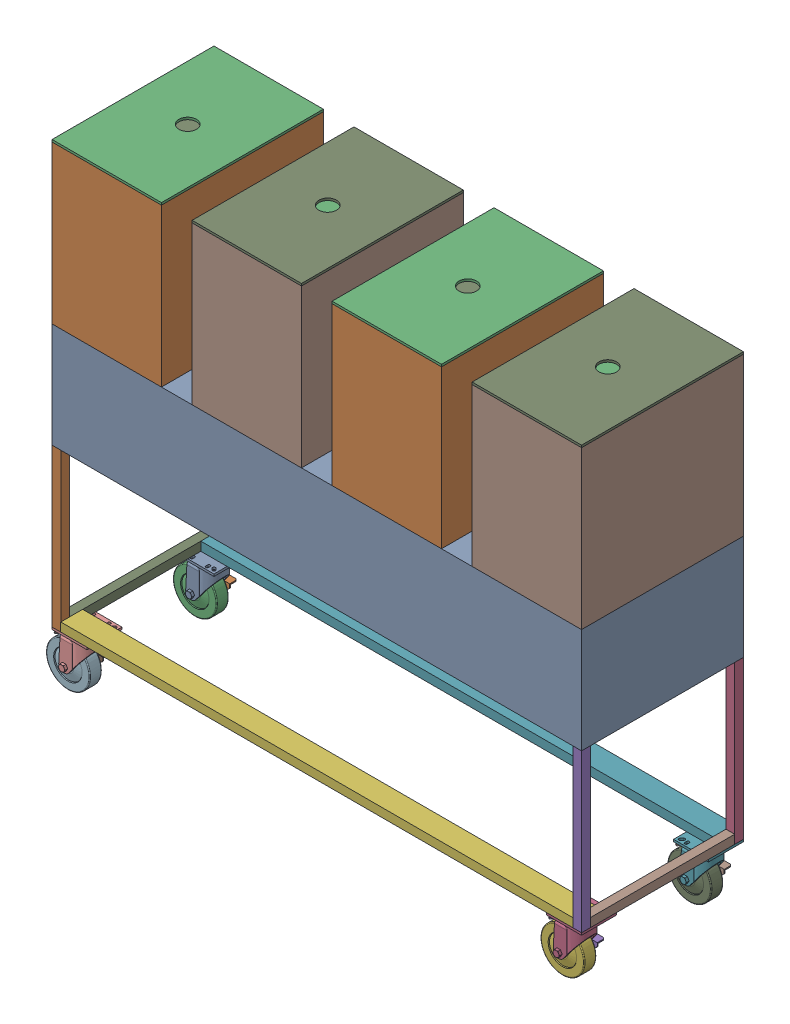
SolidWorks assembly Basic Assembly V1, configuration Default. Lengths in mm.
Overall size (1587.55 1393.83 474.36).
278 component instances, 11 part files, 3 mates.
Components (placement in the parent):
- Base Assembly-1: Base Assembly [Default] at (-1007.5115 421.629 254.1407) size (1587.55 930.27 474.36)
  - Base-1: Base [Default] at origin size (1536.7 304.8 469.9)
  - Base Leg-2: Base Leg [Default] at (0 -304.8 0) size (25.4 457.2 25.4)
  - Base Leg-3: Base Leg [Default] at (0 -304.8 -444.5) size (25.4 457.2 25.4)
  - Base Leg-4: Base Leg [Default] at (1511.3 -304.8 -444.5) size (25.4 457.2 25.4)
  - Base Leg-5: Base Leg [Default] at (1511.3 -304.8 0) size (25.4 457.2 25.4)
  - Long Leg Support-3: Long Leg Support [Default] at (25.146 -762 0) size (1486.15 25.4 63.5)
  - Long Leg Support-4: Long Leg Support [Default] at (25.146 -762 -406.4) size (1486.15 25.4 63.5)
  - Short Leg Support-3: Short Leg Support [Default] at (1536.7 -762 -21.336) x (0 0 -1) z (1 0 0) size (423.16 25.4 25.4)
  - Short Leg Support-4: Short Leg Support [Default] at (0 -762 -448.564) x (0 0 1) z (-1 0 0) size (423.16 25.4 25.4)
  - Caster Wheels-1: Caster Wheels [28925T74] at (50.75 -762 -50.75) size (152.35 168.28 105.96)
  - Caster Wheels-2: Caster Wheels [28925T74] at (50.75 -762 -419.15) size (152.35 168.28 105.96)
  - Caster Wheels-3: Caster Wheels [28925T74] at (1485.95 -762 -50.75) size (152.35 168.28 105.96)
  - Caster Wheels-4: Caster Wheels [28925T74] at (1485.95 -762 -419.15) size (152.35 168.28 105.96)
- Drying Racks Inside Chamber v1-4: Drying Racks Inside Chamber v1 [Default] at (-796.5651 486.7741 116.773) x (0 0 1) z (-1 0 0) size (469.9 463.55 317.5)
  - Stacked Tray Assembly-1: Stacked Tray Assembly [Default] at (-61.8185 38.0151 -6.3555) size (406.4 115.52 254)
    - Bottom Tray Assembly-1: Bottom Tray Assembly [Default] at (173.9076 -76.6729 -13.7937) size (406.4 76.81 254)
      - Perforated Tray-1: Perforated Tray [92725T36] at (-209.6714 56.3674 72.3455) size (406.4 0.61 254)
      - Tray Base-1: Tray Base [89825K319] at (-406.5214 -13.7874 72.3455) size (12.7 12.7 254)
      - Tray Base-2: Tray Base [89825K319] at (-12.8214 -13.7874 72.3455) size (12.7 12.7 254)
      - Tray Sides-1: Tray Sides [89825K319] at (-12.8214 24.3126 192.9955) x (1 0 0) z (0 -1 0) size (12.7 12.7 63.5)
      - Tray Sides-2: Tray Sides [89825K319] at (-406.5214 24.3126 192.9955) x (1 0 0) z (0 -1 0) size (12.7 12.7 63.5)
      - Tray Sides-3: Tray Sides [89825K319] at (-12.8214 24.3126 -48.3045) x (1 0 0) z (0 -1 0) size (12.7 12.7 63.5)
      - Tray Sides-4: Tray Sides [89825K319] at (-406.5214 24.3126 -48.3045) x (1 0 0) z (0 -1 0) size (12.7 12.7 63.5)
    - Additional Tray Assembly-1: Additional Tray Assembly [Default] at (65.2935 16.9544 6.2103) size (406.4 38.71 254)
      - Perforated Tray-1: Perforated Tray [92725T36] at (-101.0573 1.4498 52.3416) size (406.4 0.61 254)
      - Additional Tray Legs-1: Additional Tray Legs [8457K25] at (-299.4948 -17.905 174.5791) x (1 0 0) z (0 1 0) size (9.53 9.53 38.1)
      - Additional Tray Legs-2: Additional Tray Legs [8457K25] at (97.3802 -17.905 174.5791) x (1 0 0) z (0 1 0) size (9.53 9.53 38.1)
      - Additional Tray Legs-3: Additional Tray Legs [8457K25] at (-299.4948 -17.905 -69.8959) x (1 0 0) z (0 1 0) size (9.53 9.53 38.1)
      - Additional Tray Legs-4: Additional Tray Legs [8457K25] at (97.3802 -17.905 -69.8959) x (1 0 0) z (0 1 0) size (9.53 9.53 38.1)
    - Additional Tray Assembly-7: Additional Tray Assembly [Default] at (65.2935 55.0544 6.2103) size (406.4 38.71 254)
      - Perforated Tray-1: Perforated Tray [92725T36] at (-101.0573 1.4498 52.3416) size (406.4 0.61 254)
      - Additional Tray Legs-1: Additional Tray Legs [8457K25] at (-299.4948 -17.905 174.5791) x (1 0 0) z (0 1 0) size (9.53 9.53 38.1)
      - Additional Tray Legs-2: Additional Tray Legs [8457K25] at (97.3802 -17.905 174.5791) x (1 0 0) z (0 1 0) size (9.53 9.53 38.1)
      - Additional Tray Legs-3: Additional Tray Legs [8457K25] at (-299.4948 -17.905 -69.8959) x (1 0 0) z (0 1 0) size (9.53 9.53 38.1)
      - Additional Tray Legs-4: Additional Tray Legs [8457K25] at (97.3802 -17.905 -69.8959) x (1 0 0) z (0 1 0) size (9.53 9.53 38.1)
    - Additional Tray Assembly-8: Additional Tray Assembly [Default] at (65.2935 93.1544 6.2103) size (406.4 38.71 254)
      - Perforated Tray-1: Perforated Tray [92725T36] at (-101.0573 1.4498 52.3416) size (406.4 0.61 254)
      - Additional Tray Legs-1: Additional Tray Legs [8457K25] at (-299.4948 -17.905 174.5791) x (1 0 0) z (0 1 0) size (9.53 9.53 38.1)
      - Additional Tray Legs-2: Additional Tray Legs [8457K25] at (97.3802 -17.905 174.5791) x (1 0 0) z (0 1 0) size (9.53 9.53 38.1)
      - Additional Tray Legs-3: Additional Tray Legs [8457K25] at (-299.4948 -17.905 -69.8959) x (1 0 0) z (0 1 0) size (9.53 9.53 38.1)
      - Additional Tray Legs-4: Additional Tray Legs [8457K25] at (97.3802 -17.905 -69.8959) x (1 0 0) z (0 1 0) size (9.53 9.53 38.1)
    - Additional Tray Assembly-9: Additional Tray Assembly [Default] at (65.2935 131.2544 6.2103) size (406.4 38.71 254)
      - Perforated Tray-1: Perforated Tray [92725T36] at (-101.0573 1.4498 52.3416) size (406.4 0.61 254)
      - Additional Tray Legs-1: Additional Tray Legs [8457K25] at (-299.4948 -17.905 174.5791) x (1 0 0) z (0 1 0) size (9.53 9.53 38.1)
      - Additional Tray Legs-2: Additional Tray Legs [8457K25] at (97.3802 -17.905 174.5791) x (1 0 0) z (0 1 0) size (9.53 9.53 38.1)
      - Additional Tray Legs-3: Additional Tray Legs [8457K25] at (-299.4948 -17.905 -69.8959) x (1 0 0) z (0 1 0) size (9.53 9.53 38.1)
      - Additional Tray Legs-4: Additional Tray Legs [8457K25] at (97.3802 -17.905 -69.8959) x (1 0 0) z (0 1 0) size (9.53 9.53 38.1)
    - Additional Tray Assembly-10: Additional Tray Assembly [Default] at (65.2935 169.3544 6.2103) size (406.4 38.71 254)
      - Perforated Tray-1: Perforated Tray [92725T36] at (-101.0573 1.4498 52.3416) size (406.4 0.61 254)
      - Additional Tray Legs-1: Additional Tray Legs [8457K25] at (-299.4948 -17.905 174.5791) x (1 0 0) z (0 1 0) size (9.53 9.53 38.1)
      - Additional Tray Legs-2: Additional Tray Legs [8457K25] at (97.3802 -17.905 174.5791) x (1 0 0) z (0 1 0) size (9.53 9.53 38.1)
      - Additional Tray Legs-3: Additional Tray Legs [8457K25] at (-299.4948 -17.905 -69.8959) x (1 0 0) z (0 1 0) size (9.53 9.53 38.1)
      - Additional Tray Legs-4: Additional Tray Legs [8457K25] at (97.3802 -17.905 -69.8959) x (1 0 0) z (0 1 0) size (9.53 9.53 38.1)
    - Additional Tray Assembly-11: Additional Tray Assembly [Default] at (65.2935 207.4544 6.2103) size (406.4 38.71 254)
      - Perforated Tray-1: Perforated Tray [92725T36] at (-101.0573 1.4498 52.3416) size (406.4 0.61 254)
      - Additional Tray Legs-1: Additional Tray Legs [8457K25] at (-299.4948 -17.905 174.5791) x (1 0 0) z (0 1 0) size (9.53 9.53 38.1)
      - Additional Tray Legs-2: Additional Tray Legs [8457K25] at (97.3802 -17.905 174.5791) x (1 0 0) z (0 1 0) size (9.53 9.53 38.1)
      - Additional Tray Legs-3: Additional Tray Legs [8457K25] at (-299.4948 -17.905 -69.8959) x (1 0 0) z (0 1 0) size (9.53 9.53 38.1)
      - Additional Tray Legs-4: Additional Tray Legs [8457K25] at (97.3802 -17.905 -69.8959) x (1 0 0) z (0 1 0) size (9.53 9.53 38.1)
    - Additional Tray Assembly-12: Additional Tray Assembly [Default] at (65.2935 245.5544 6.2103) size (406.4 38.71 254)
      - Perforated Tray-1: Perforated Tray [92725T36] at (-101.0573 1.4498 52.3416) size (406.4 0.61 254)
      - Additional Tray Legs-1: Additional Tray Legs [8457K25] at (-299.4948 -17.905 174.5791) x (1 0 0) z (0 1 0) size (9.53 9.53 38.1)
      - Additional Tray Legs-2: Additional Tray Legs [8457K25] at (97.3802 -17.905 174.5791) x (1 0 0) z (0 1 0) size (9.53 9.53 38.1)
      - Additional Tray Legs-3: Additional Tray Legs [8457K25] at (-299.4948 -17.905 -69.8959) x (1 0 0) z (0 1 0) size (9.53 9.53 38.1)
      - Additional Tray Legs-4: Additional Tray Legs [8457K25] at (97.3802 -17.905 -69.8959) x (1 0 0) z (0 1 0) size (9.53 9.53 38.1)
    - Additional Tray Assembly-13: Additional Tray Assembly [Default] at (65.2935 283.6544 6.2103) size (406.4 38.71 254)
      - Perforated Tray-1: Perforated Tray [92725T36] at (-101.0573 1.4498 52.3416) size (406.4 0.61 254)
      - Additional Tray Legs-1: Additional Tray Legs [8457K25] at (-299.4948 -17.905 174.5791) x (1 0 0) z (0 1 0) size (9.53 9.53 38.1)
      - Additional Tray Legs-2: Additional Tray Legs [8457K25] at (97.3802 -17.905 174.5791) x (1 0 0) z (0 1 0) size (9.53 9.53 38.1)
      - Additional Tray Legs-3: Additional Tray Legs [8457K25] at (-299.4948 -17.905 -69.8959) x (1 0 0) z (0 1 0) size (9.53 9.53 38.1)
      - Additional Tray Legs-4: Additional Tray Legs [8457K25] at (97.3802 -17.905 -69.8959) x (1 0 0) z (0 1 0) size (9.53 9.53 38.1)
    - Additional Tray Assembly-14: Additional Tray Assembly [Default] at (65.2935 321.7544 6.2103) size (406.4 38.71 254)
      - Perforated Tray-1: Perforated Tray [92725T36] at (-101.0573 1.4498 52.3416) size (406.4 0.61 254)
      - Additional Tray Legs-1: Additional Tray Legs [8457K25] at (-299.4948 -17.905 174.5791) x (1 0 0) z (0 1 0) size (9.53 9.53 38.1)
      - Additional Tray Legs-2: Additional Tray Legs [8457K25] at (97.3802 -17.905 174.5791) x (1 0 0) z (0 1 0) size (9.53 9.53 38.1)
      - Additional Tray Legs-3: Additional Tray Legs [8457K25] at (-299.4948 -17.905 -69.8959) x (1 0 0) z (0 1 0) size (9.53 9.53 38.1)
      - Additional Tray Legs-4: Additional Tray Legs [8457K25] at (97.3802 -17.905 -69.8959) x (1 0 0) z (0 1 0) size (9.53 9.53 38.1)
  - Drying Chamber-1: Drying Chamber [Default] at (-326.1823 -65.1452 204.5964) x (1 0 0) z (0 1 0) size (469.9 317.5 457.2)
  - Drying Chamber Roof-1: Drying Chamber Roof [Default] at (-332.5323 392.0548 210.9464) size (469.9 6.35 317.5)
- Drying Racks Inside Chamber v1-5: Drying Racks Inside Chamber v1 [Default] at (-390.1651 486.7741 116.773) x (0 0 1) z (-1 0 0) size (469.9 463.55 317.5)
  - Stacked Tray Assembly-1: Stacked Tray Assembly [Default] at (-61.8185 38.0151 -6.3555) size (406.4 115.52 254)
    - Bottom Tray Assembly-1: Bottom Tray Assembly [Default] at (173.9076 -76.6729 -13.7937) size (406.4 76.81 254)
      - Perforated Tray-1: Perforated Tray [92725T36] at (-209.6714 56.3674 72.3455) size (406.4 0.61 254)
      - Tray Base-1: Tray Base [89825K319] at (-406.5214 -13.7874 72.3455) size (12.7 12.7 254)
      - Tray Base-2: Tray Base [89825K319] at (-12.8214 -13.7874 72.3455) size (12.7 12.7 254)
      - Tray Sides-1: Tray Sides [89825K319] at (-12.8214 24.3126 192.9955) x (1 0 0) z (0 -1 0) size (12.7 12.7 63.5)
      - Tray Sides-2: Tray Sides [89825K319] at (-406.5214 24.3126 192.9955) x (1 0 0) z (0 -1 0) size (12.7 12.7 63.5)
      - Tray Sides-3: Tray Sides [89825K319] at (-12.8214 24.3126 -48.3045) x (1 0 0) z (0 -1 0) size (12.7 12.7 63.5)
      - Tray Sides-4: Tray Sides [89825K319] at (-406.5214 24.3126 -48.3045) x (1 0 0) z (0 -1 0) size (12.7 12.7 63.5)
    - Additional Tray Assembly-1: Additional Tray Assembly [Default] at (65.2935 16.9544 6.2103) size (406.4 38.71 254)
      - Perforated Tray-1: Perforated Tray [92725T36] at (-101.0573 1.4498 52.3416) size (406.4 0.61 254)
      - Additional Tray Legs-1: Additional Tray Legs [8457K25] at (-299.4948 -17.905 174.5791) x (1 0 0) z (0 1 0) size (9.53 9.53 38.1)
      - Additional Tray Legs-2: Additional Tray Legs [8457K25] at (97.3802 -17.905 174.5791) x (1 0 0) z (0 1 0) size (9.53 9.53 38.1)
      - Additional Tray Legs-3: Additional Tray Legs [8457K25] at (-299.4948 -17.905 -69.8959) x (1 0 0) z (0 1 0) size (9.53 9.53 38.1)
      - Additional Tray Legs-4: Additional Tray Legs [8457K25] at (97.3802 -17.905 -69.8959) x (1 0 0) z (0 1 0) size (9.53 9.53 38.1)
    - Additional Tray Assembly-7: Additional Tray Assembly [Default] at (65.2935 55.0544 6.2103) size (406.4 38.71 254)
      - Perforated Tray-1: Perforated Tray [92725T36] at (-101.0573 1.4498 52.3416) size (406.4 0.61 254)
      - Additional Tray Legs-1: Additional Tray Legs [8457K25] at (-299.4948 -17.905 174.5791) x (1 0 0) z (0 1 0) size (9.53 9.53 38.1)
      - Additional Tray Legs-2: Additional Tray Legs [8457K25] at (97.3802 -17.905 174.5791) x (1 0 0) z (0 1 0) size (9.53 9.53 38.1)
      - Additional Tray Legs-3: Additional Tray Legs [8457K25] at (-299.4948 -17.905 -69.8959) x (1 0 0) z (0 1 0) size (9.53 9.53 38.1)
      - Additional Tray Legs-4: Additional Tray Legs [8457K25] at (97.3802 -17.905 -69.8959) x (1 0 0) z (0 1 0) size (9.53 9.53 38.1)
    - Additional Tray Assembly-8: Additional Tray Assembly [Default] at (65.2935 93.1544 6.2103) size (406.4 38.71 254)
      - Perforated Tray-1: Perforated Tray [92725T36] at (-101.0573 1.4498 52.3416) size (406.4 0.61 254)
      - Additional Tray Legs-1: Additional Tray Legs [8457K25] at (-299.4948 -17.905 174.5791) x (1 0 0) z (0 1 0) size (9.53 9.53 38.1)
      - Additional Tray Legs-2: Additional Tray Legs [8457K25] at (97.3802 -17.905 174.5791) x (1 0 0) z (0 1 0) size (9.53 9.53 38.1)
      - Additional Tray Legs-3: Additional Tray Legs [8457K25] at (-299.4948 -17.905 -69.8959) x (1 0 0) z (0 1 0) size (9.53 9.53 38.1)
      - Additional Tray Legs-4: Additional Tray Legs [8457K25] at (97.3802 -17.905 -69.8959) x (1 0 0) z (0 1 0) size (9.53 9.53 38.1)
    - Additional Tray Assembly-9: Additional Tray Assembly [Default] at (65.2935 131.2544 6.2103) size (406.4 38.71 254)
      - Perforated Tray-1: Perforated Tray [92725T36] at (-101.0573 1.4498 52.3416) size (406.4 0.61 254)
      - Additional Tray Legs-1: Additional Tray Legs [8457K25] at (-299.4948 -17.905 174.5791) x (1 0 0) z (0 1 0) size (9.53 9.53 38.1)
      - Additional Tray Legs-2: Additional Tray Legs [8457K25] at (97.3802 -17.905 174.5791) x (1 0 0) z (0 1 0) size (9.53 9.53 38.1)
      - Additional Tray Legs-3: Additional Tray Legs [8457K25] at (-299.4948 -17.905 -69.8959) x (1 0 0) z (0 1 0) size (9.53 9.53 38.1)
      - Additional Tray Legs-4: Additional Tray Legs [8457K25] at (97.3802 -17.905 -69.8959) x (1 0 0) z (0 1 0) size (9.53 9.53 38.1)
    - Additional Tray Assembly-10: Additional Tray Assembly [Default] at (65.2935 169.3544 6.2103) size (406.4 38.71 254)
      - Perforated Tray-1: Perforated Tray [92725T36] at (-101.0573 1.4498 52.3416) size (406.4 0.61 254)
      - Additional Tray Legs-1: Additional Tray Legs [8457K25] at (-299.4948 -17.905 174.5791) x (1 0 0) z (0 1 0) size (9.53 9.53 38.1)
      - Additional Tray Legs-2: Additional Tray Legs [8457K25] at (97.3802 -17.905 174.5791) x (1 0 0) z (0 1 0) size (9.53 9.53 38.1)
      - Additional Tray Legs-3: Additional Tray Legs [8457K25] at (-299.4948 -17.905 -69.8959) x (1 0 0) z (0 1 0) size (9.53 9.53 38.1)
      - Additional Tray Legs-4: Additional Tray Legs [8457K25] at (97.3802 -17.905 -69.8959) x (1 0 0) z (0 1 0) size (9.53 9.53 38.1)
    - Additional Tray Assembly-11: Additional Tray Assembly [Default] at (65.2935 207.4544 6.2103) size (406.4 38.71 254)
      - Perforated Tray-1: Perforated Tray [92725T36] at (-101.0573 1.4498 52.3416) size (406.4 0.61 254)
      - Additional Tray Legs-1: Additional Tray Legs [8457K25] at (-299.4948 -17.905 174.5791) x (1 0 0) z (0 1 0) size (9.53 9.53 38.1)
      - Additional Tray Legs-2: Additional Tray Legs [8457K25] at (97.3802 -17.905 174.5791) x (1 0 0) z (0 1 0) size (9.53 9.53 38.1)
      - Additional Tray Legs-3: Additional Tray Legs [8457K25] at (-299.4948 -17.905 -69.8959) x (1 0 0) z (0 1 0) size (9.53 9.53 38.1)
      - Additional Tray Legs-4: Additional Tray Legs [8457K25] at (97.3802 -17.905 -69.8959) x (1 0 0) z (0 1 0) size (9.53 9.53 38.1)
    - Additional Tray Assembly-12: Additional Tray Assembly [Default] at (65.2935 245.5544 6.2103) size (406.4 38.71 254)
      - Perforated Tray-1: Perforated Tray [92725T36] at (-101.0573 1.4498 52.3416) size (406.4 0.61 254)
      - Additional Tray Legs-1: Additional Tray Legs [8457K25] at (-299.4948 -17.905 174.5791) x (1 0 0) z (0 1 0) size (9.53 9.53 38.1)
      - Additional Tray Legs-2: Additional Tray Legs [8457K25] at (97.3802 -17.905 174.5791) x (1 0 0) z (0 1 0) size (9.53 9.53 38.1)
      - Additional Tray Legs-3: Additional Tray Legs [8457K25] at (-299.4948 -17.905 -69.8959) x (1 0 0) z (0 1 0) size (9.53 9.53 38.1)
      - Additional Tray Legs-4: Additional Tray Legs [8457K25] at (97.3802 -17.905 -69.8959) x (1 0 0) z (0 1 0) size (9.53 9.53 38.1)
    - Additional Tray Assembly-13: Additional Tray Assembly [Default] at (65.2935 283.6544 6.2103) size (406.4 38.71 254)
      - Perforated Tray-1: Perforated Tray [92725T36] at (-101.0573 1.4498 52.3416) size (406.4 0.61 254)
      - Additional Tray Legs-1: Additional Tray Legs [8457K25] at (-299.4948 -17.905 174.5791) x (1 0 0) z (0 1 0) size (9.53 9.53 38.1)
      - Additional Tray Legs-2: Additional Tray Legs [8457K25] at (97.3802 -17.905 174.5791) x (1 0 0) z (0 1 0) size (9.53 9.53 38.1)
      - Additional Tray Legs-3: Additional Tray Legs [8457K25] at (-299.4948 -17.905 -69.8959) x (1 0 0) z (0 1 0) size (9.53 9.53 38.1)
      - Additional Tray Legs-4: Additional Tray Legs [8457K25] at (97.3802 -17.905 -69.8959) x (1 0 0) z (0 1 0) size (9.53 9.53 38.1)
    - Additional Tray Assembly-14: Additional Tray Assembly [Default] at (65.2935 321.7544 6.2103) size (406.4 38.71 254)
      - Perforated Tray-1: Perforated Tray [92725T36] at (-101.0573 1.4498 52.3416) size (406.4 0.61 254)
      - Additional Tray Legs-1: Additional Tray Legs [8457K25] at (-299.4948 -17.905 174.5791) x (1 0 0) z (0 1 0) size (9.53 9.53 38.1)
      - Additional Tray Legs-2: Additional Tray Legs [8457K25] at (97.3802 -17.905 174.5791) x (1 0 0) z (0 1 0) size (9.53 9.53 38.1)
      - Additional Tray Legs-3: Additional Tray Legs [8457K25] at (-299.4948 -17.905 -69.8959) x (1 0 0) z (0 1 0) size (9.53 9.53 38.1)
      - Additional Tray Legs-4: Additional Tray Legs [8457K25] at (97.3802 -17.905 -69.8959) x (1 0 0) z (0 1 0) size (9.53 9.53 38.1)
  - Drying Chamber-1: Drying Chamber [Default] at (-326.1823 -65.1452 204.5964) x (1 0 0) z (0 1 0) size (469.9 317.5 457.2)
  - Drying Chamber Roof-1: Drying Chamber Roof [Default] at (-332.5323 392.0548 210.9464) size (469.9 6.35 317.5)
- Drying Racks Inside Chamber v1-6: Drying Racks Inside Chamber v1 [Default] at (16.2349 486.7741 116.773) x (0 0 1) z (-1 0 0) size (469.9 463.55 317.5)
  - Stacked Tray Assembly-1: Stacked Tray Assembly [Default] at (-61.8185 38.0151 -6.3555) size (406.4 115.52 254)
    - Bottom Tray Assembly-1: Bottom Tray Assembly [Default] at (173.9076 -76.6729 -13.7937) size (406.4 76.81 254)
      - Perforated Tray-1: Perforated Tray [92725T36] at (-209.6714 56.3674 72.3455) size (406.4 0.61 254)
      - Tray Base-1: Tray Base [89825K319] at (-406.5214 -13.7874 72.3455) size (12.7 12.7 254)
      - Tray Base-2: Tray Base [89825K319] at (-12.8214 -13.7874 72.3455) size (12.7 12.7 254)
      - Tray Sides-1: Tray Sides [89825K319] at (-12.8214 24.3126 192.9955) x (1 0 0) z (0 -1 0) size (12.7 12.7 63.5)
      - Tray Sides-2: Tray Sides [89825K319] at (-406.5214 24.3126 192.9955) x (1 0 0) z (0 -1 0) size (12.7 12.7 63.5)
      - Tray Sides-3: Tray Sides [89825K319] at (-12.8214 24.3126 -48.3045) x (1 0 0) z (0 -1 0) size (12.7 12.7 63.5)
      - Tray Sides-4: Tray Sides [89825K319] at (-406.5214 24.3126 -48.3045) x (1 0 0) z (0 -1 0) size (12.7 12.7 63.5)
    - Additional Tray Assembly-1: Additional Tray Assembly [Default] at (65.2935 16.9544 6.2103) size (406.4 38.71 254)
      - Perforated Tray-1: Perforated Tray [92725T36] at (-101.0573 1.4498 52.3416) size (406.4 0.61 254)
      - Additional Tray Legs-1: Additional Tray Legs [8457K25] at (-299.4948 -17.905 174.5791) x (1 0 0) z (0 1 0) size (9.53 9.53 38.1)
      - Additional Tray Legs-2: Additional Tray Legs [8457K25] at (97.3802 -17.905 174.5791) x (1 0 0) z (0 1 0) size (9.53 9.53 38.1)
      - Additional Tray Legs-3: Additional Tray Legs [8457K25] at (-299.4948 -17.905 -69.8959) x (1 0 0) z (0 1 0) size (9.53 9.53 38.1)
      - Additional Tray Legs-4: Additional Tray Legs [8457K25] at (97.3802 -17.905 -69.8959) x (1 0 0) z (0 1 0) size (9.53 9.53 38.1)
    - Additional Tray Assembly-7: Additional Tray Assembly [Default] at (65.2935 55.0544 6.2103) size (406.4 38.71 254)
      - Perforated Tray-1: Perforated Tray [92725T36] at (-101.0573 1.4498 52.3416) size (406.4 0.61 254)
      - Additional Tray Legs-1: Additional Tray Legs [8457K25] at (-299.4948 -17.905 174.5791) x (1 0 0) z (0 1 0) size (9.53 9.53 38.1)
      - Additional Tray Legs-2: Additional Tray Legs [8457K25] at (97.3802 -17.905 174.5791) x (1 0 0) z (0 1 0) size (9.53 9.53 38.1)
      - Additional Tray Legs-3: Additional Tray Legs [8457K25] at (-299.4948 -17.905 -69.8959) x (1 0 0) z (0 1 0) size (9.53 9.53 38.1)
      - Additional Tray Legs-4: Additional Tray Legs [8457K25] at (97.3802 -17.905 -69.8959) x (1 0 0) z (0 1 0) size (9.53 9.53 38.1)
    - Additional Tray Assembly-8: Additional Tray Assembly [Default] at (65.2935 93.1544 6.2103) size (406.4 38.71 254)
      - Perforated Tray-1: Perforated Tray [92725T36] at (-101.0573 1.4498 52.3416) size (406.4 0.61 254)
      - Additional Tray Legs-1: Additional Tray Legs [8457K25] at (-299.4948 -17.905 174.5791) x (1 0 0) z (0 1 0) size (9.53 9.53 38.1)
      - Additional Tray Legs-2: Additional Tray Legs [8457K25] at (97.3802 -17.905 174.5791) x (1 0 0) z (0 1 0) size (9.53 9.53 38.1)
      - Additional Tray Legs-3: Additional Tray Legs [8457K25] at (-299.4948 -17.905 -69.8959) x (1 0 0) z (0 1 0) size (9.53 9.53 38.1)
      - Additional Tray Legs-4: Additional Tray Legs [8457K25] at (97.3802 -17.905 -69.8959) x (1 0 0) z (0 1 0) size (9.53 9.53 38.1)
    - Additional Tray Assembly-9: Additional Tray Assembly [Default] at (65.2935 131.2544 6.2103) size (406.4 38.71 254)
      - Perforated Tray-1: Perforated Tray [92725T36] at (-101.0573 1.4498 52.3416) size (406.4 0.61 254)
      - Additional Tray Legs-1: Additional Tray Legs [8457K25] at (-299.4948 -17.905 174.5791) x (1 0 0) z (0 1 0) size (9.53 9.53 38.1)
      - Additional Tray Legs-2: Additional Tray Legs [8457K25] at (97.3802 -17.905 174.5791) x (1 0 0) z (0 1 0) size (9.53 9.53 38.1)
      - Additional Tray Legs-3: Additional Tray Legs [8457K25] at (-299.4948 -17.905 -69.8959) x (1 0 0) z (0 1 0) size (9.53 9.53 38.1)
      - Additional Tray Legs-4: Additional Tray Legs [8457K25] at (97.3802 -17.905 -69.8959) x (1 0 0) z (0 1 0) size (9.53 9.53 38.1)
    - Additional Tray Assembly-10: Additional Tray Assembly [Default] at (65.2935 169.3544 6.2103) size (406.4 38.71 254)
      - Perforated Tray-1: Perforated Tray [92725T36] at (-101.0573 1.4498 52.3416) size (406.4 0.61 254)
      - Additional Tray Legs-1: Additional Tray Legs [8457K25] at (-299.4948 -17.905 174.5791) x (1 0 0) z (0 1 0) size (9.53 9.53 38.1)
      - Additional Tray Legs-2: Additional Tray Legs [8457K25] at (97.3802 -17.905 174.5791) x (1 0 0) z (0 1 0) size (9.53 9.53 38.1)
      - Additional Tray Legs-3: Additional Tray Legs [8457K25] at (-299.4948 -17.905 -69.8959) x (1 0 0) z (0 1 0) size (9.53 9.53 38.1)
      - Additional Tray Legs-4: Additional Tray Legs [8457K25] at (97.3802 -17.905 -69.8959) x (1 0 0) z (0 1 0) size (9.53 9.53 38.1)
    - Additional Tray Assembly-11: Additional Tray Assembly [Default] at (65.2935 207.4544 6.2103) size (406.4 38.71 254)
      - Perforated Tray-1: Perforated Tray [92725T36] at (-101.0573 1.4498 52.3416) size (406.4 0.61 254)
      - Additional Tray Legs-1: Additional Tray Legs [8457K25] at (-299.4948 -17.905 174.5791) x (1 0 0) z (0 1 0) size (9.53 9.53 38.1)
      - Additional Tray Legs-2: Additional Tray Legs [8457K25] at (97.3802 -17.905 174.5791) x (1 0 0) z (0 1 0) size (9.53 9.53 38.1)
      - Additional Tray Legs-3: Additional Tray Legs [8457K25] at (-299.4948 -17.905 -69.8959) x (1 0 0) z (0 1 0) size (9.53 9.53 38.1)
      - Additional Tray Legs-4: Additional Tray Legs [8457K25] at (97.3802 -17.905 -69.8959) x (1 0 0) z (0 1 0) size (9.53 9.53 38.1)
    - Additional Tray Assembly-12: Additional Tray Assembly [Default] at (65.2935 245.5544 6.2103) size (406.4 38.71 254)
      - Perforated Tray-1: Perforated Tray [92725T36] at (-101.0573 1.4498 52.3416) size (406.4 0.61 254)
      - Additional Tray Legs-1: Additional Tray Legs [8457K25] at (-299.4948 -17.905 174.5791) x (1 0 0) z (0 1 0) size (9.53 9.53 38.1)
      - Additional Tray Legs-2: Additional Tray Legs [8457K25] at (97.3802 -17.905 174.5791) x (1 0 0) z (0 1 0) size (9.53 9.53 38.1)
      - Additional Tray Legs-3: Additional Tray Legs [8457K25] at (-299.4948 -17.905 -69.8959) x (1 0 0) z (0 1 0) size (9.53 9.53 38.1)
      - Additional Tray Legs-4: Additional Tray Legs [8457K25] at (97.3802 -17.905 -69.8959) x (1 0 0) z (0 1 0) size (9.53 9.53 38.1)
    - Additional Tray Assembly-13: Additional Tray Assembly [Default] at (65.2935 283.6544 6.2103) size (406.4 38.71 254)
      - Perforated Tray-1: Perforated Tray [92725T36] at (-101.0573 1.4498 52.3416) size (406.4 0.61 254)
      - Additional Tray Legs-1: Additional Tray Legs [8457K25] at (-299.4948 -17.905 174.5791) x (1 0 0) z (0 1 0) size (9.53 9.53 38.1)
      - Additional Tray Legs-2: Additional Tray Legs [8457K25] at (97.3802 -17.905 174.5791) x (1 0 0) z (0 1 0) size (9.53 9.53 38.1)
      - Additional Tray Legs-3: Additional Tray Legs [8457K25] at (-299.4948 -17.905 -69.8959) x (1 0 0) z (0 1 0) size (9.53 9.53 38.1)
      - Additional Tray Legs-4: Additional Tray Legs [8457K25] at (97.3802 -17.905 -69.8959) x (1 0 0) z (0 1 0) size (9.53 9.53 38.1)
    - Additional Tray Assembly-14: Additional Tray Assembly [Default] at (65.2935 321.7544 6.2103) size (406.4 38.71 254)
      - Perforated Tray-1: Perforated Tray [92725T36] at (-101.0573 1.4498 52.3416) size (406.4 0.61 254)
      - Additional Tray Legs-1: Additional Tray Legs [8457K25] at (-299.4948 -17.905 174.5791) x (1 0 0) z (0 1 0) size (9.53 9.53 38.1)
      - Additional Tray Legs-2: Additional Tray Legs [8457K25] at (97.3802 -17.905 174.5791) x (1 0 0) z (0 1 0) size (9.53 9.53 38.1)
      - Additional Tray Legs-3: Additional Tray Legs [8457K25] at (-299.4948 -17.905 -69.8959) x (1 0 0) z (0 1 0) size (9.53 9.53 38.1)
      - Additional Tray Legs-4: Additional Tray Legs [8457K25] at (97.3802 -17.905 -69.8959) x (1 0 0) z (0 1 0) size (9.53 9.53 38.1)
  - Drying Chamber-1: Drying Chamber [Default] at (-326.1823 -65.1452 204.5964) x (1 0 0) z (0 1 0) size (469.9 317.5 457.2)
  - Drying Chamber Roof-1: Drying Chamber Roof [Default] at (-332.5323 392.0548 210.9464) size (469.9 6.35 317.5)
- Drying Racks Inside Chamber v1-7: Drying Racks Inside Chamber v1 [Default] at (422.6349 486.7741 116.773) x (0 0 1) z (-1 0 0) size (469.9 463.55 317.5)
  - Stacked Tray Assembly-1: Stacked Tray Assembly [Default] at (-61.8185 38.0151 -6.3555) size (406.4 115.52 254)
    - Bottom Tray Assembly-1: Bottom Tray Assembly [Default] at (173.9076 -76.6729 -13.7937) size (406.4 76.81 254)
      - Perforated Tray-1: Perforated Tray [92725T36] at (-209.6714 56.3674 72.3455) size (406.4 0.61 254)
      - Tray Base-1: Tray Base [89825K319] at (-406.5214 -13.7874 72.3455) size (12.7 12.7 254)
      - Tray Base-2: Tray Base [89825K319] at (-12.8214 -13.7874 72.3455) size (12.7 12.7 254)
      - Tray Sides-1: Tray Sides [89825K319] at (-12.8214 24.3126 192.9955) x (1 0 0) z (0 -1 0) size (12.7 12.7 63.5)
      - Tray Sides-2: Tray Sides [89825K319] at (-406.5214 24.3126 192.9955) x (1 0 0) z (0 -1 0) size (12.7 12.7 63.5)
      - Tray Sides-3: Tray Sides [89825K319] at (-12.8214 24.3126 -48.3045) x (1 0 0) z (0 -1 0) size (12.7 12.7 63.5)
      - Tray Sides-4: Tray Sides [89825K319] at (-406.5214 24.3126 -48.3045) x (1 0 0) z (0 -1 0) size (12.7 12.7 63.5)
    - Additional Tray Assembly-1: Additional Tray Assembly [Default] at (65.2935 16.9544 6.2103) size (406.4 38.71 254)
      - Perforated Tray-1: Perforated Tray [92725T36] at (-101.0573 1.4498 52.3416) size (406.4 0.61 254)
      - Additional Tray Legs-1: Additional Tray Legs [8457K25] at (-299.4948 -17.905 174.5791) x (1 0 0) z (0 1 0) size (9.53 9.53 38.1)
      - Additional Tray Legs-2: Additional Tray Legs [8457K25] at (97.3802 -17.905 174.5791) x (1 0 0) z (0 1 0) size (9.53 9.53 38.1)
      - Additional Tray Legs-3: Additional Tray Legs [8457K25] at (-299.4948 -17.905 -69.8959) x (1 0 0) z (0 1 0) size (9.53 9.53 38.1)
      - Additional Tray Legs-4: Additional Tray Legs [8457K25] at (97.3802 -17.905 -69.8959) x (1 0 0) z (0 1 0) size (9.53 9.53 38.1)
    - Additional Tray Assembly-7: Additional Tray Assembly [Default] at (65.2935 55.0544 6.2103) size (406.4 38.71 254)
      - Perforated Tray-1: Perforated Tray [92725T36] at (-101.0573 1.4498 52.3416) size (406.4 0.61 254)
      - Additional Tray Legs-1: Additional Tray Legs [8457K25] at (-299.4948 -17.905 174.5791) x (1 0 0) z (0 1 0) size (9.53 9.53 38.1)
      - Additional Tray Legs-2: Additional Tray Legs [8457K25] at (97.3802 -17.905 174.5791) x (1 0 0) z (0 1 0) size (9.53 9.53 38.1)
      - Additional Tray Legs-3: Additional Tray Legs [8457K25] at (-299.4948 -17.905 -69.8959) x (1 0 0) z (0 1 0) size (9.53 9.53 38.1)
      - Additional Tray Legs-4: Additional Tray Legs [8457K25] at (97.3802 -17.905 -69.8959) x (1 0 0) z (0 1 0) size (9.53 9.53 38.1)
    - Additional Tray Assembly-8: Additional Tray Assembly [Default] at (65.2935 93.1544 6.2103) size (406.4 38.71 254)
      - Perforated Tray-1: Perforated Tray [92725T36] at (-101.0573 1.4498 52.3416) size (406.4 0.61 254)
      - Additional Tray Legs-1: Additional Tray Legs [8457K25] at (-299.4948 -17.905 174.5791) x (1 0 0) z (0 1 0) size (9.53 9.53 38.1)
      - Additional Tray Legs-2: Additional Tray Legs [8457K25] at (97.3802 -17.905 174.5791) x (1 0 0) z (0 1 0) size (9.53 9.53 38.1)
      - Additional Tray Legs-3: Additional Tray Legs [8457K25] at (-299.4948 -17.905 -69.8959) x (1 0 0) z (0 1 0) size (9.53 9.53 38.1)
      - Additional Tray Legs-4: Additional Tray Legs [8457K25] at (97.3802 -17.905 -69.8959) x (1 0 0) z (0 1 0) size (9.53 9.53 38.1)
    - Additional Tray Assembly-9: Additional Tray Assembly [Default] at (65.2935 131.2544 6.2103) size (406.4 38.71 254)
      - Perforated Tray-1: Perforated Tray [92725T36] at (-101.0573 1.4498 52.3416) size (406.4 0.61 254)
      - Additional Tray Legs-1: Additional Tray Legs [8457K25] at (-299.4948 -17.905 174.5791) x (1 0 0) z (0 1 0) size (9.53 9.53 38.1)
      - Additional Tray Legs-2: Additional Tray Legs [8457K25] at (97.3802 -17.905 174.5791) x (1 0 0) z (0 1 0) size (9.53 9.53 38.1)
      - Additional Tray Legs-3: Additional Tray Legs [8457K25] at (-299.4948 -17.905 -69.8959) x (1 0 0) z (0 1 0) size (9.53 9.53 38.1)
      - Additional Tray Legs-4: Additional Tray Legs [8457K25] at (97.3802 -17.905 -69.8959) x (1 0 0) z (0 1 0) size (9.53 9.53 38.1)
    - Additional Tray Assembly-10: Additional Tray Assembly [Default] at (65.2935 169.3544 6.2103) size (406.4 38.71 254)
      - Perforated Tray-1: Perforated Tray [92725T36] at (-101.0573 1.4498 52.3416) size (406.4 0.61 254)
      - Additional Tray Legs-1: Additional Tray Legs [8457K25] at (-299.4948 -17.905 174.5791) x (1 0 0) z (0 1 0) size (9.53 9.53 38.1)
      - Additional Tray Legs-2: Additional Tray Legs [8457K25] at (97.3802 -17.905 174.5791) x (1 0 0) z (0 1 0) size (9.53 9.53 38.1)
      - Additional Tray Legs-3: Additional Tray Legs [8457K25] at (-299.4948 -17.905 -69.8959) x (1 0 0) z (0 1 0) size (9.53 9.53 38.1)
      - Additional Tray Legs-4: Additional Tray Legs [8457K25] at (97.3802 -17.905 -69.8959) x (1 0 0) z (0 1 0) size (9.53 9.53 38.1)
    - Additional Tray Assembly-11: Additional Tray Assembly [Default] at (65.2935 207.4544 6.2103) size (406.4 38.71 254)
      - Perforated Tray-1: Perforated Tray [92725T36] at (-101.0573 1.4498 52.3416) size (406.4 0.61 254)
      - Additional Tray Legs-1: Additional Tray Legs [8457K25] at (-299.4948 -17.905 174.5791) x (1 0 0) z (0 1 0) size (9.53 9.53 38.1)
      - Additional Tray Legs-2: Additional Tray Legs [8457K25] at (97.3802 -17.905 174.5791) x (1 0 0) z (0 1 0) size (9.53 9.53 38.1)
      - Additional Tray Legs-3: Additional Tray Legs [8457K25] at (-299.4948 -17.905 -69.8959) x (1 0 0) z (0 1 0) size (9.53 9.53 38.1)
      - Additional Tray Legs-4: Additional Tray Legs [8457K25] at (97.3802 -17.905 -69.8959) x (1 0 0) z (0 1 0) size (9.53 9.53 38.1)
    - Additional Tray Assembly-12: Additional Tray Assembly [Default] at (65.2935 245.5544 6.2103) size (406.4 38.71 254)
      - Perforated Tray-1: Perforated Tray [92725T36] at (-101.0573 1.4498 52.3416) size (406.4 0.61 254)
      - Additional Tray Legs-1: Additional Tray Legs [8457K25] at (-299.4948 -17.905 174.5791) x (1 0 0) z (0 1 0) size (9.53 9.53 38.1)
      - Additional Tray Legs-2: Additional Tray Legs [8457K25] at (97.3802 -17.905 174.5791) x (1 0 0) z (0 1 0) size (9.53 9.53 38.1)
      - Additional Tray Legs-3: Additional Tray Legs [8457K25] at (-299.4948 -17.905 -69.8959) x (1 0 0) z (0 1 0) size (9.53 9.53 38.1)
      - Additional Tray Legs-4: Additional Tray Legs [8457K25] at (97.3802 -17.905 -69.8959) x (1 0 0) z (0 1 0) size (9.53 9.53 38.1)
    - Additional Tray Assembly-13: Additional Tray Assembly [Default] at (65.2935 283.6544 6.2103) size (406.4 38.71 254)
      - Perforated Tray-1: Perforated Tray [92725T36] at (-101.0573 1.4498 52.3416) size (406.4 0.61 254)
      - Additional Tray Legs-1: Additional Tray Legs [8457K25] at (-299.4948 -17.905 174.5791) x (1 0 0) z (0 1 0) size (9.53 9.53 38.1)
      - Additional Tray Legs-2: Additional Tray Legs [8457K25] at (97.3802 -17.905 174.5791) x (1 0 0) z (0 1 0) size (9.53 9.53 38.1)
      - Additional Tray Legs-3: Additional Tray Legs [8457K25] at (-299.4948 -17.905 -69.8959) x (1 0 0) z (0 1 0) size (9.53 9.53 38.1)
      - Additional Tray Legs-4: Additional Tray Legs [8457K25] at (97.3802 -17.905 -69.8959) x (1 0 0) z (0 1 0) size (9.53 9.53 38.1)
    - Additional Tray Assembly-14: Additional Tray Assembly [Default] at (65.2935 321.7544 6.2103) size (406.4 38.71 254)
      - Perforated Tray-1: Perforated Tray [92725T36] at (-101.0573 1.4498 52.3416) size (406.4 0.61 254)
      - Additional Tray Legs-1: Additional Tray Legs [8457K25] at (-299.4948 -17.905 174.5791) x (1 0 0) z (0 1 0) size (9.53 9.53 38.1)
      - Additional Tray Legs-2: Additional Tray Legs [8457K25] at (97.3802 -17.905 174.5791) x (1 0 0) z (0 1 0) size (9.53 9.53 38.1)
      - Additional Tray Legs-3: Additional Tray Legs [8457K25] at (-299.4948 -17.905 -69.8959) x (1 0 0) z (0 1 0) size (9.53 9.53 38.1)
      - Additional Tray Legs-4: Additional Tray Legs [8457K25] at (97.3802 -17.905 -69.8959) x (1 0 0) z (0 1 0) size (9.53 9.53 38.1)
  - Drying Chamber-1: Drying Chamber [Default] at (-326.1823 -65.1452 204.5964) x (1 0 0) z (0 1 0) size (469.9 317.5 457.2)
  - Drying Chamber Roof-1: Drying Chamber Roof [Default] at (-332.5323 392.0548 210.9464) size (469.9 6.35 317.5)
Mates (geometry in assembly coordinates):
- Coincident1: coincident anti-aligned: plane of Base Assembly-1/Base-1 through (-1007.5115 421.629 254.1407) normal (0 1 0); plane of Drying Racks Inside Chamber v1-4/Drying Chamber-1 through (-1001.1615 421.629 -209.4093) normal (0 -1 0)
- Coincident4: coincident aligned: plane of Base Assembly-1/Base-1 through (-1007.5115 116.829 -215.7593) normal (0 0 -1); plane of Drying Racks Inside Chamber v1-4/Drying Chamber-1 through (-1001.1615 421.629 -215.7593) normal (0 0 -1)
- Coincident5: coincident aligned: plane of Base Assembly-1/Base-1 through (-1007.5115 116.829 254.1407) normal (-1 0 0); plane of Drying Racks Inside Chamber v1-4/Drying Chamber-1 through (-1007.5115 421.629 -209.4093) normal (-1 0 0)
